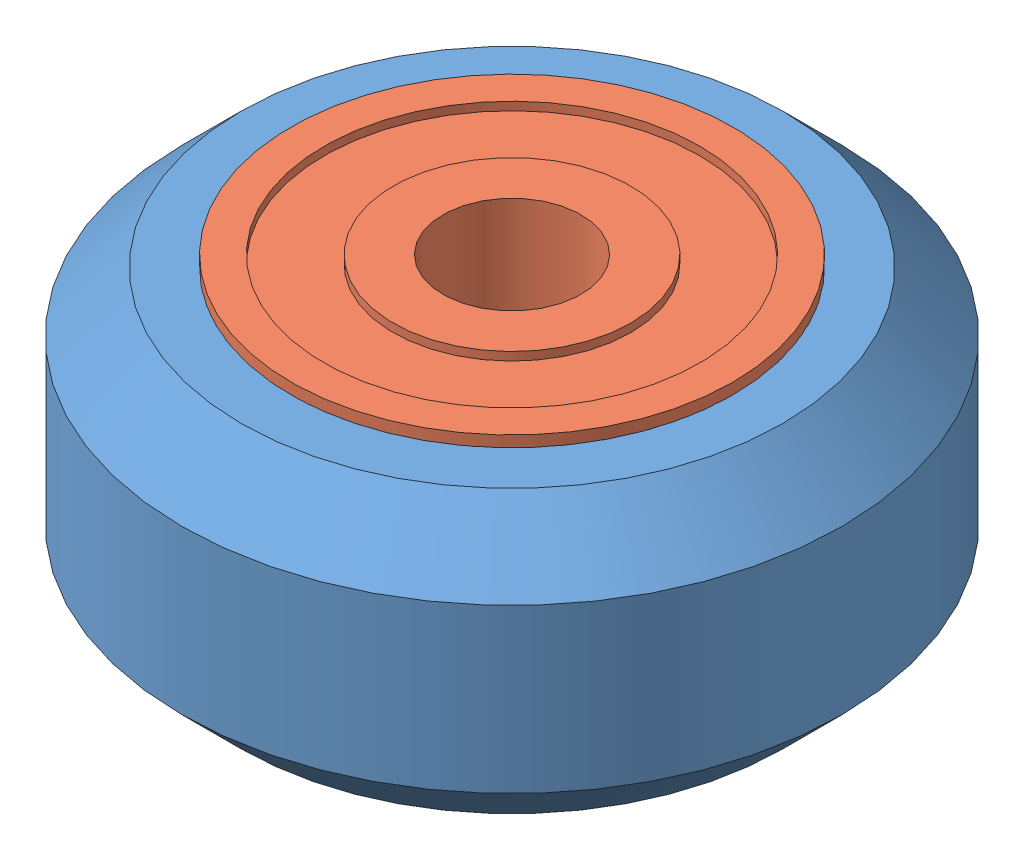
SolidWorks assembly User Library-WHL-VSLOT-DLRN, configuration Straight. Lengths in mm.
Overall size (23.9 11 23.9).
4 component instances, 3 part files, 6 mates.
Components (placement in the parent):
- User Library-WHL-VSLOT-DLRN_Solid V Wheel-1: User Library-WHL-VSLOT-DLRN_Solid V Wheel [Default] x (0 -1 0) z (0 0 1) size (10.2 23.9 23.9)
- User Library-WHL-VSLOT-DLRN_Ball Bearing 5 x 16 x 5-1: User Library-WHL-VSLOT-DLRN_Ball Bearing 5 x 16 x 5 [Default] at (0 -3 0) x (0 -1 0) z (0.990411 0 0.138155) size (5 16 16)
- User Library-WHL-VSLOT-DLRN_Ball Bearing 5 x 16 x 5-2: User Library-WHL-VSLOT-DLRN_Ball Bearing 5 x 16 x 5 [Default] at (0 3 0) x (0 1 0) z (-0.887666 0 -0.460488) size (5 16 16)
- User Library-WHL-VSLOT-DLRN_Precision Shim 10 x 5 x 1-1: User Library-WHL-VSLOT-DLRN_Precision Shim 10 x 5 x 1 [Default] at (0 -0.5 0) x (0.977063 0 -0.212952) z (0.212952 0 0.977063) size (10 1 10)
Mates (geometry in assembly coordinates):
- Concentric1: concentric anti-aligned: cylinder of User Library-WHL-VSLOT-DLRN_Solid V Wheel-1 through (0 0 0) axis (0 -1 0) radius 8; cylinder of User Library-WHL-VSLOT-DLRN_Ball Bearing 5 x 16 x 5-2 through (0 3 0) axis (0 1 0) radius 8
- Coincident4: coincident anti-aligned: plane of User Library-WHL-VSLOT-DLRN_Solid V Wheel-1 through (7 0.5 0) normal (0 1 0); plane of User Library-WHL-VSLOT-DLRN_Ball Bearing 5 x 16 x 5-2 through (3.1313 0.5 -6.0361) normal (0 -1 0)
- Concentric3: concentric aligned: cylinder of User Library-WHL-VSLOT-DLRN_Solid V Wheel-1 through (0 0 0) axis (0 -1 0) radius 8; cylinder of User Library-WHL-VSLOT-DLRN_Ball Bearing 5 x 16 x 5-1 through (0 -3 0) axis (0 -1 0) radius 8
- Coincident6: coincident anti-aligned: plane of User Library-WHL-VSLOT-DLRN_Solid V Wheel-1 through (7 -0.5 0) normal (0 -1 0); plane of User Library-WHL-VSLOT-DLRN_Ball Bearing 5 x 16 x 5-1 through (0.9395 -0.5 -6.7348) normal (0 1 0)
- Concentric4: concentric anti-aligned: cylinder of User Library-WHL-VSLOT-DLRN_Ball Bearing 5 x 16 x 5-2 through (0 3 0) axis (0 1 0) radius 2.5; cylinder of User Library-WHL-VSLOT-DLRN_Precision Shim 10 x 5 x 1-1 through (0 0.5 0) axis (0 -1 0) radius 2.5
- Coincident7: coincident anti-aligned: plane of User Library-WHL-VSLOT-DLRN_Ball Bearing 5 x 16 x 5-2 through (1.1512 0.5 -2.2192) normal (0 -1 0); plane of User Library-WHL-VSLOT-DLRN_Precision Shim 10 x 5 x 1-1 through (0 0.5 0) normal (0 1 0)
